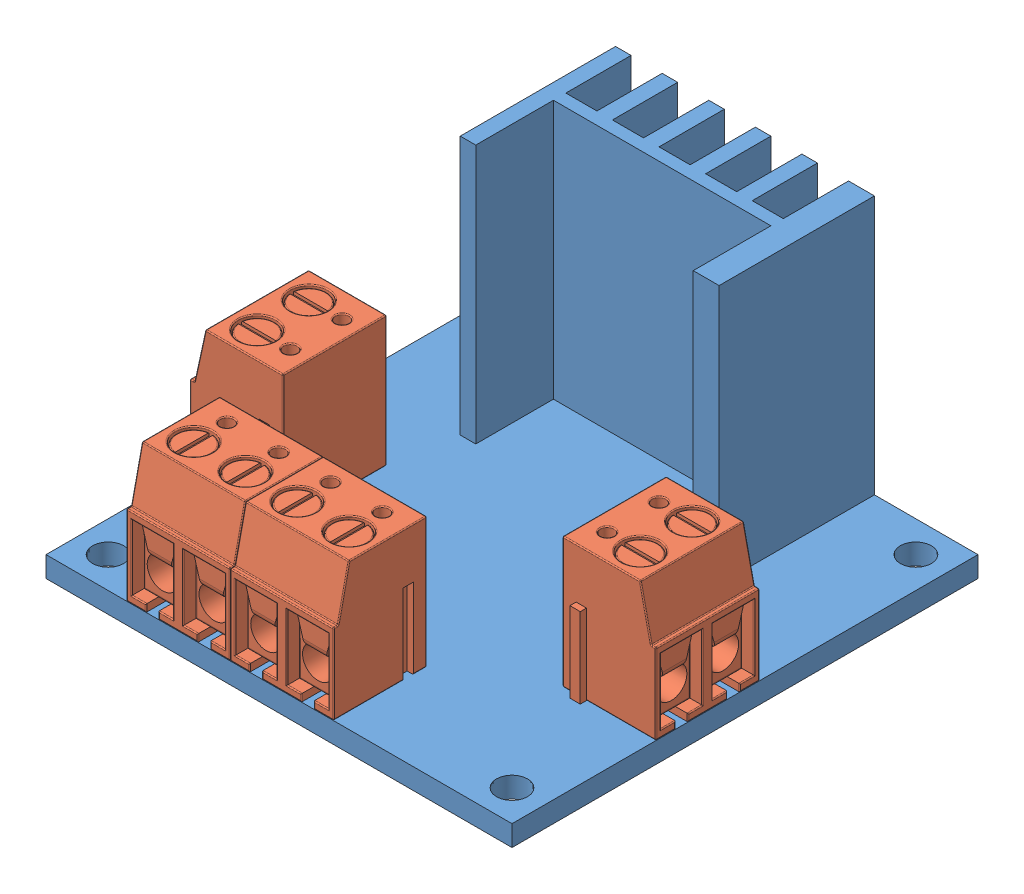
SolidWorks assembly L298, configuration Default. Lengths in mm.
Overall size (45 28.6 45).
5 component instances, 2 part files, 10 mates.
Components (placement in the parent):
- Dimensi L298-1: Dimensi L298 [Default] at origin size (45 27 45)
- DG 300 (2p)-1: DG 300 (2p) [Default] at (13.5 8.3 3.6104) x (0 0 -1) z (1 0 0) size (10.6 16.2 9)
- DG 300 (2p)-2: DG 300 (2p) [Default] at (-13.5 8.3 3.6104) x (0 0 1) z (-1 0 0) size (10.6 16.2 9)
- DG 300 (2p)-3: DG 300 (2p) [Default] at (-9.7299 8.3 13.5) size (10.6 16.2 9)
- DG 300 (2p)-4: DG 300 (2p) [Default] at (0.2701 8.3 13.5) size (10.6 16.2 9)
Mates (geometry in assembly coordinates):
- Coincident1: coincident: plane of Dimensi L298-1 through (0 2 0) normal (0 1 0); plane of DG 300 (2p)-1 through (22.5 2 8.6104) normal (0 -1 0)
- Coincident2: coincident: plane of DG 300 (2p)-1 through (22.5 14.6 8.6104) normal (0 1 0); plane of DG 300 (2p)-4 through (-4.7299 14.6 22.5) normal (0 1 0)
- Coincident3: coincident: plane of DG 300 (2p)-3 through (-14.7299 14.6 22.5) normal (0 1 0); plane of DG 300 (2p)-4 through (-4.7299 14.6 22.5) normal (0 1 0)
- Coincident4: coincident: plane of DG 300 (2p)-2 through (-22.5 14.6 -1.3896) normal (0 1 0); plane of DG 300 (2p)-4 through (-4.7299 14.6 22.5) normal (0 1 0)
- Coincident5: coincident: plane of DG 300 (2p)-3 through (-9.7299 8.3 22.5) normal (0 0 1); plane of DG 300 (2p)-4 through (0.2701 8.3 22.5) normal (0 0 1)
- Coincident6: coincident: plane of DG 300 (2p)-3 through (-4.7299 2 22.5) normal (1 0 0); plane of DG 300 (2p)-4 through (-4.7299 2 22.5) normal (-1 0 0)
- Coincident7: coincident: plane of DG 300 (2p)-1 through (22.5 2 8.6104) normal (0 0 1); plane of DG 300 (2p)-2 through (-22.5 2 8.6104) normal (0 0 1)
- Coincident8: coincident: plane of Dimensi L298-1 through (22.5 2 22.5) normal (0 0 1); plane of DG 300 (2p)-4 through (0.2701 8.3 22.5) normal (0 0 1)
- Coincident9: coincident: plane of Dimensi L298-1 through (22.5 2 22.5) normal (1 0 0); plane of DG 300 (2p)-1 through (22.5 8.3 3.6104) normal (1 0 0)
- Coincident10: coincident: plane of Dimensi L298-1 through (-22.5 2 22.5) normal (-1 0 0); plane of DG 300 (2p)-2 through (-22.5 8.3 3.6104) normal (-1 0 0)
